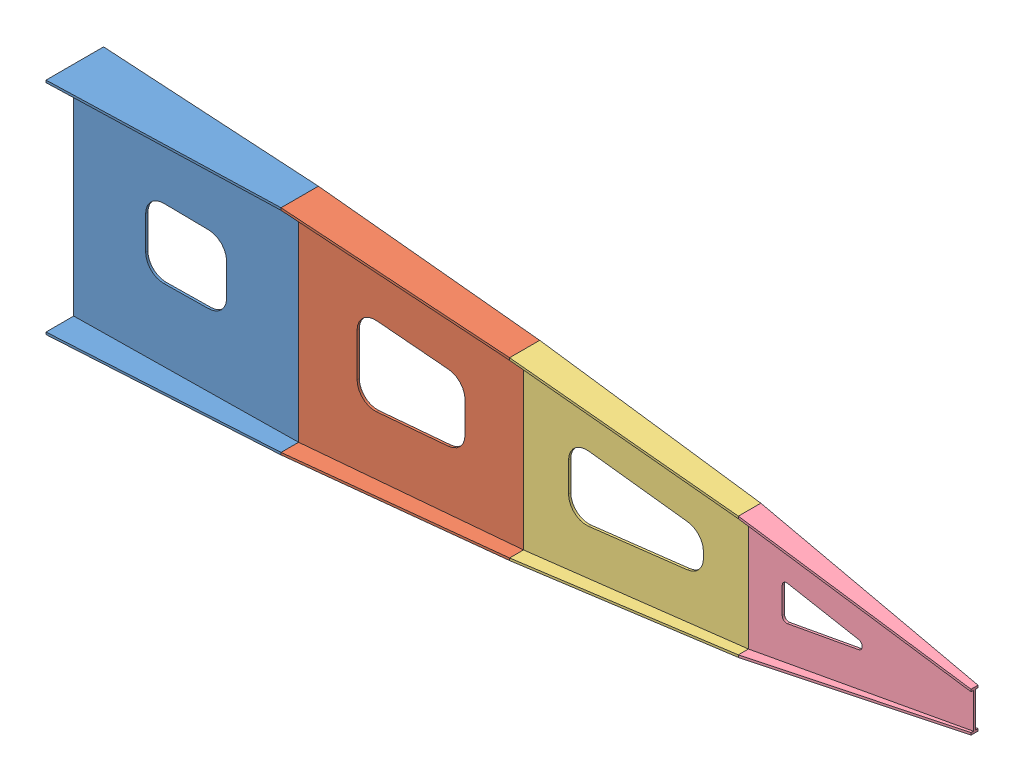
SolidWorks assembly 1.02 tolerance assembly, configuration Default. Lengths in mm.
Overall size (4000 980 256).
4 component instances, 4 part files, 9 mates.
Components (placement in the parent):
- 1-1: 1 [Default] at (-775.9263 612.0858 1043.8579) size (1000 980 256)
- 2-2: 2 [Default] at (224.0737 612.0858 1043.8579) size (1000 952 166)
- 3-2: 3 [Default] at (1224.0737 612.0858 1043.8579) size (1000 781 134)
- 4-2: 4 [Default] at (2224.0737 612.0858 1043.8579) size (1000 544 100)
Mates (geometry in assembly coordinates):
- Coincident39: coincident anti-aligned: plane of 1-1 through (224.0737 612.0858 1043.8579) normal (1 0 0); plane of 2-2 through (224.0737 612.0858 1043.8579) normal (-1 0 0)
- Coincident40: coincident anti-aligned: plane of 2-2 through (1224.0737 612.0858 1043.8579) normal (1 0 0); plane of 3-2 through (1224.0737 612.0858 1043.8579) normal (-1 0 0)
- Coincident42: coincident: point of 1-1; point of 2-2
- Coincident43: coincident: point of 1-1; point of 2-2
- Coincident44: coincident: point of 2-2; point of 3-2
- Coincident46: coincident: point of 2-2; point of 3-2
- Coincident49: coincident: point of 3-2; point of 4-2
- Coincident52: coincident aligned: plane of 3-2 through (1224.0737 612.0858 1053.8579) normal (0 0 1); plane of 4-2 through (2224.0737 612.0858 1053.8579) normal (0 0 1)
- Coincident53: coincident: point of 3-2; point of 4-2
